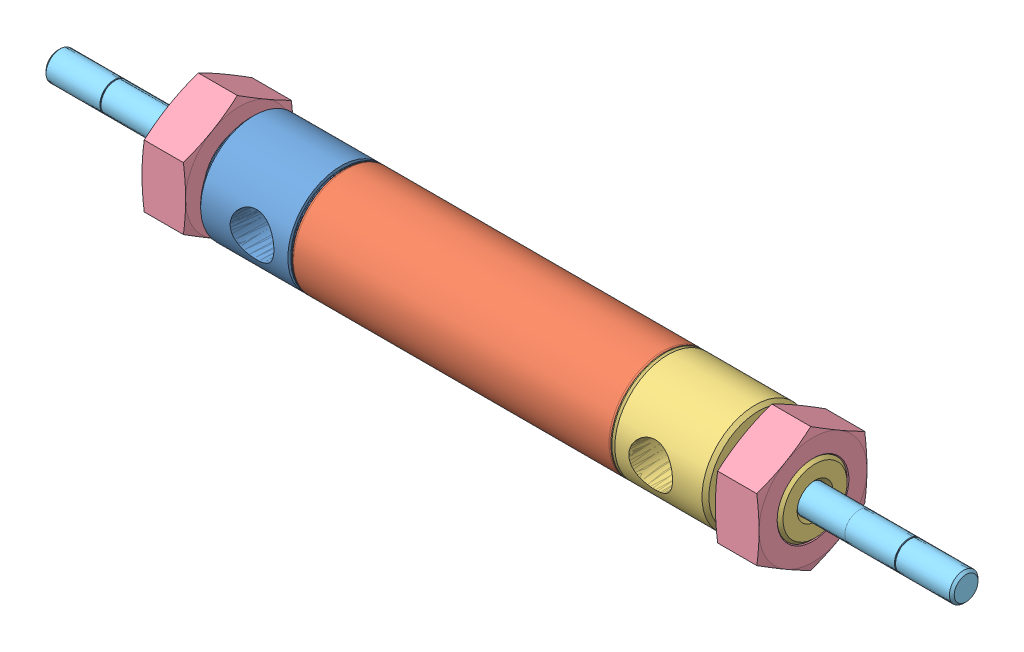
SolidWorks assembly 061_5-DXDE, configuration Default. Lengths in mm.
Overall size (200.91 27.57 26.6).
7 component instances, 6 part files, 17 mates.
Components (placement in the parent):
- 061_5-DXDE0000_0_dummy-1: 061_5-DXDE0000_0_dummy [Default] at origin
- 06R000-1_5_rod_guide-1: 06R000-1_5_rod_guide [Default] at origin size (38.89 23.52 23.52)
- 06R-2_7880-1: 06R-2_7880 [Default] at (33.2994 0 0) size (72.17 23.52 23.52)
- 06R000-0_rod_guide-1: 06R000-0_rod_guide [Default] at (137.414 0 0) x (-1 0 0) z (0 0 1) size (38.89 23.52 23.52)
- D-9-1: D-9 [Default] at (127.3048 0 0) x (0 0 -1) z (-1 0 0) size (23.88 27.57 9.65)
- D-9-2: D-9 [Default] at (10.1092 0 0) x (0 0 -1) z (1 0 0) size (23.88 27.57 9.65)
- 061_5-DXDE0_rod-1: 061_5-DXDE0_rod [Default] at (-17.3858 0 0) x (1 0 0) z (0 0.210375 -0.977621) size (200.91 22.39 22.39)
Mates (geometry in assembly coordinates):
- Distance2: distance = 0 mm aligned: plane of 06R000-1_5_rod_guide-1 through (0 0 0) normal (1 0 0); plane of 061_5-DXDE0000_0_dummy-1 through (0 0 0) normal (1 0 0)
- Coincident1: coincident aligned: line of 061_5-DXDE0000_0_dummy-1 through (80.9 0 0) axis (-1 0 0); line of 06R000-1_5_rod_guide-1 through (80.9 0 0) axis (-1 0 0)
- Angle3: planar angle = 0 rad aligned: plane of 06R000-1_5_rod_guide-1 through (0 0 0) normal (0 0 -1); plane of 061_5-DXDE0000_0_dummy-1 through (0 0 0) normal (0 0 -1)
- Distance4: distance = 0 mm aligned: plane of 06R-2_7880-1 through (33.2994 0 0) normal (1 0 0); plane of 06R000-1_5_rod_guide-1 through (33.2994 0 0) normal (1 0 0)
- Coincident2: coincident aligned: line of 06R000-1_5_rod_guide-1 through (80.9 0 0) axis (-1 0 0); line of 06R-2_7880-1 through (114.1994 0 0) axis (-1 0 0)
- Angle6: planar angle = 0 rad aligned: plane of 06R-2_7880-1 through (33.2994 0 0) normal (0 0 -1); plane of 06R000-1_5_rod_guide-1 through (0 0 0) normal (0 0 -1)
- Distance5: distance = 0 mm anti-aligned: plane of 06R000-0_rod_guide-1; plane of 06R-2_7880-1 through (104.1146 0 0) normal (1 0 0)
- Coincident3: coincident anti-aligned: line of 06R-2_7880-1 through (114.1994 0 0) axis (-1 0 0); line of 06R000-0_rod_guide-1 through (56.514 0 0) axis (1 0 0)
- Angle9: planar angle = 0 rad aligned: plane of 06R000-0_rod_guide-1 through (137.414 0 0) normal (0 0 -1); plane of 06R-2_7880-1 through (33.2994 0 0) normal (0 0 -1)
- Distance7: distance = 0 mm aligned: plane of D-9-1 through (127.3048 0 0) normal (-1 0 0); plane of 06R000-0_rod_guide-1
- Coincident4: coincident aligned: line of 06R000-0_rod_guide-1 through (56.514 0 0) axis (1 0 0); line of D-9-1 through (46.4048 0 0) axis (1 0 0)
- Angle12: planar angle = 0 rad aligned: plane of D-9-1; plane of 06R000-0_rod_guide-1 through (137.414 0 0) normal (0 0 -1)
- Distance9: distance = 0 mm aligned: plane of D-9-2 through (10.1092 0 0) normal (1 0 0); plane of 06R000-1_5_rod_guide-1 through (10.1092 0 0) normal (1 0 0)
- Coincident5: coincident aligned: line of 06R000-1_5_rod_guide-1 through (80.9 0 0) axis (-1 0 0); line of D-9-2 through (91.0092 0 0) axis (-1 0 0)
- Angle15: planar angle = 0 rad aligned: plane of D-9-2 through (10.1092 0 0) normal (0 0 -1); plane of 06R000-1_5_rod_guide-1 through (0 0 0) normal (0 0 -1)
- LimitDistance2: limit distance = -20.7142 mm: plane of 061_5-DXDE0_rod-1; plane of 06R000-1_5_rod_guide-1 through (-38.1 0 0) normal (1 0 0)
- Coincident6: coincident aligned: line of 06R000-1_5_rod_guide-1 through (80.9 0 0) axis (-1 0 0); line of 061_5-DXDE0_rod-1 through (63.5142 0 0) axis (-1 0 0)
